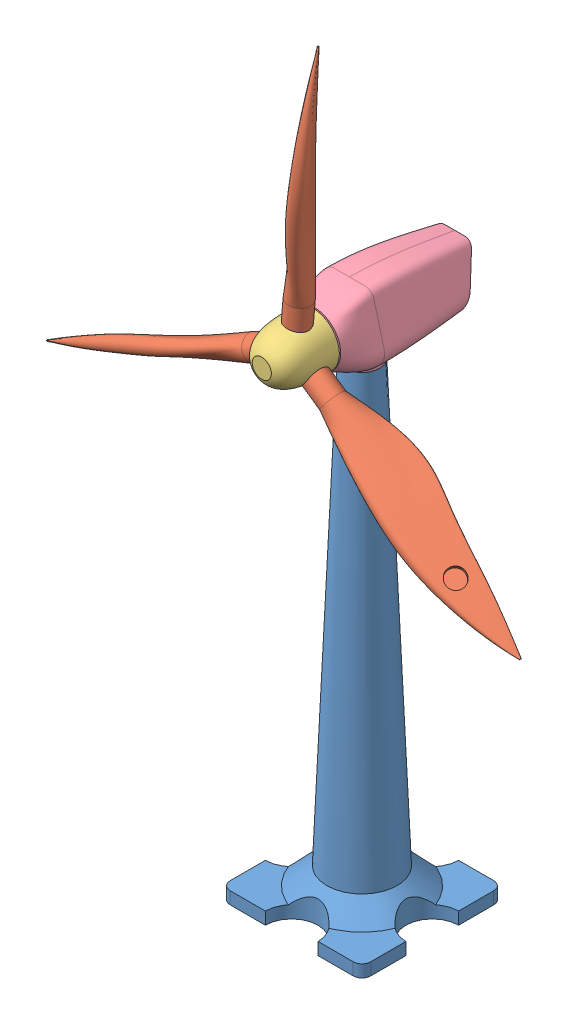
SolidWorks assembly Assembly, configuration Default. Lengths in mm.
Overall size (359.21 568.04 140.95).
6 component instances, 4 part files, 11 mates.
Components (placement in the parent):
- Wind Turbine Base-1: Wind Turbine Base [Default] at origin size (101.6 339.09 101.6)
- Wind Turbine Blade-1: Wind Turbine Blade [Default] at (6.2591 364.7439 48.1456) x (0.516916 0.74444 0.422618) z (0.241042 0.347138 -0.906308) size (16.85 190.51 45.08)
- Wind Turbine Hub-1: Wind Turbine Hub [Default] at (0 369.09 35.4456) x (0 0 -1) z (-0.570354 -0.821399 0) size (37 38.98 38.79)
- Wind Turbine Nacelle-1: Wind Turbine Nacelle [Default] at (0 369.09 9.0456) size (51.04 55.4 102.96)
- Wind Turbine Blade-2: Wind Turbine Blade [Default] at (-6.8934 365.8425 48.1456) x (0.386246 -0.819883 0.422618) z (0.180109 -0.382318 -0.906308) size (16.85 190.51 45.08)
- Wind Turbine Blade-3: Wind Turbine Blade [Default] at (0.6343 376.6836 48.1456) x (-0.903162 0.075443 0.422618) z (-0.421152 0.035179 -0.906308) size (16.85 190.51 45.08)
Mates (geometry in assembly coordinates):
- Coincident1: coincident anti-aligned: plane of Wind Turbine Base-1 through (44.45 0 -44.45) normal (0 -1 0); plane of assembly through (0 0 0) normal (0 1 0)
- Coincident2: coincident aligned: plane of Wind Turbine Base-1 through (0 0 0) normal (1 0 0); plane of assembly through (0 0 0) normal (1 0 0)
- Coincident3: coincident aligned: plane of Wind Turbine Base-1 through (0 0 0) normal (0 0 1); plane of assembly through (0 0 0) normal (0 0 1)
- Distance2: distance = 1 mm anti-aligned: plane of Wind Turbine Hub-1 through (0 369.09 35.4456) normal (0 0 -1); plane of Wind Turbine Nacelle-1 through (0 369.09 34.4456) normal (0 0 1)
- Concentric1: concentric aligned: circle of Wind Turbine Nacelle-1; circle of Wind Turbine Hub-1
- Concentric2: concentric aligned: cylinder of Wind Turbine Blade-1 through (27.1226 350.2569 48.1456) axis (-0.821399 0.570354 0) radius 8.255; cylinder of Wind Turbine Hub-1 through (15.8372 358.0931 48.1456) axis (-0.821399 0.570354 0) radius 8.255
- Coincident9: coincident anti-aligned: plane of Wind Turbine Blade-1 through (6.2591 364.7439 48.1456) normal (-0.821399 0.570354 0); plane of Wind Turbine Hub-1 through (6.2591 364.7439 48.1456) normal (0.821399 -0.570354 0)
- Angle2: planar angle = 2.70526 rad aligned: plane of Wind Turbine Blade-1 through (6.2591 364.7439 48.1456) normal (0.516916 0.74444 0.422618); plane of Wind Turbine Hub-1 through (0 369.09 35.4456) normal (-0.570354 -0.821399 0)
- Coincident13: coincident anti-aligned: plane of Wind Turbine Base-1 through (12.7 339.09 0) normal (0 1 0); plane of Wind Turbine Nacelle-1 through (0 339.09 0) normal (0 -1 0)
- Coincident14: coincident aligned: circle of Wind Turbine Base-1; circle of Wind Turbine Nacelle-1
- Coincident15: coincident aligned: plane of Wind Turbine Nacelle-1 through (0 369.09 9.0456) normal (1 0 0); plane of assembly through (0 0 0) normal (1 0 0)
